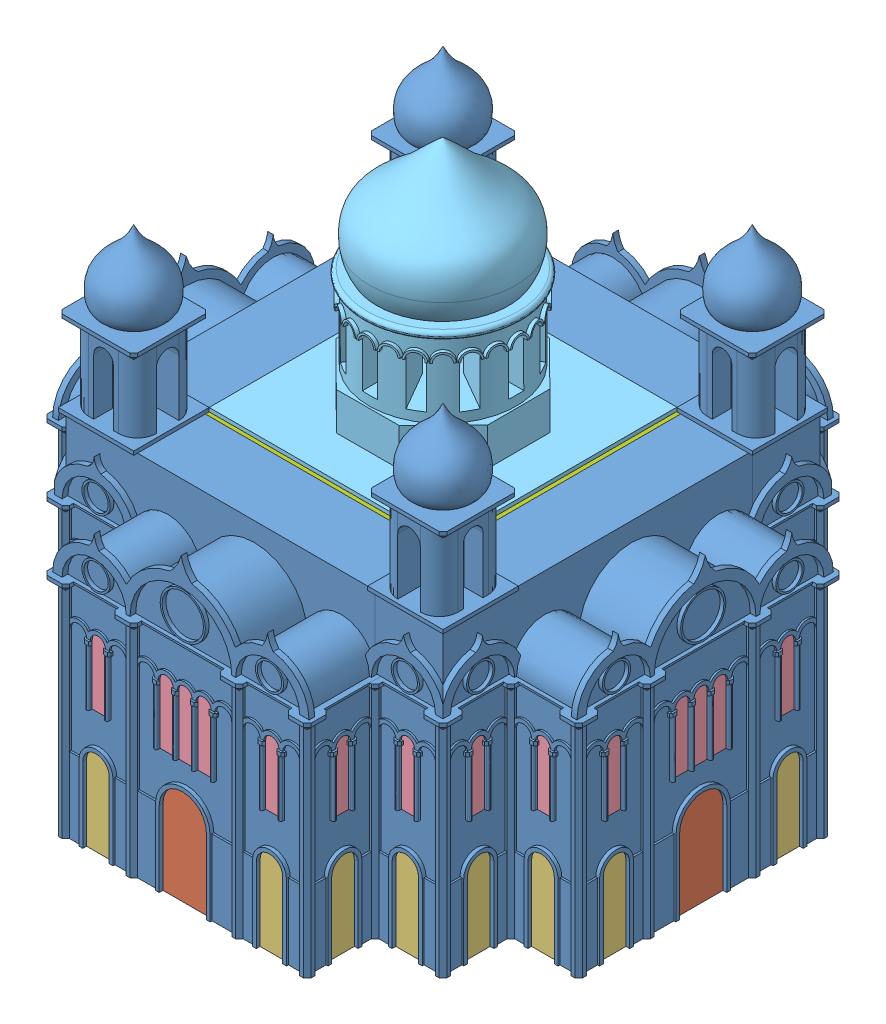
SolidWorks assembly Assem6, configuration Default. Lengths in mm.
Overall size (142 142.08 142).
71 component instances, 7 part files, 159 mates.
Components (placement in the parent):
- a4-object-wall-1: a4-object-wall [Default] at (90 0 -530.3215) x (0 0 -1) z (1 0 0) size (88 122 41)
- a4-object-bigDoor-3: a4-object-bigDoor [Default] at (117 0 -486.5715) x (0 0 -1) z (1 0 0) size (12.5 26.25 1)
- a4-object-smallDoor-1: a4-object-smallDoor [Default] at (100 0 -435.8215) x (0 0 1) z (0 -1 0) size (7 1 23.5)
- a4-object-smallDoor-2: a4-object-smallDoor [Default] at (117 0 -460.8215) x (0 0 -1) z (0 -1 0) size (7 1 23.5)
- a4-object-smallDoor-3: a4-object-smallDoor [Default] at (117 0 -506.8215) x (0 0 -1) z (0 -1 0) size (7 1 23.5)
- a4-object-smallDoor-4: a4-object-smallDoor [Default] at (105.5 0 -511.3215) x (-1 0 0) z (0 -1 0) size (7 1 23.5)
- a4-object-smallDoor-6: a4-object-smallDoor [Default] at (105.5 0 -448.3215) x (-1 0 0) z (0 -1 0) size (7 1 23.5)
- a4-object-smallDoor-7: a4-object-smallDoor [Default] at (94.5 0 -431.3215) x (1 0 0) z (0 -1 0) size (7 1 23.5)
- a4-object-window-1: a4-object-window [Default] at (93 32.25 -431.3215) size (4 18 1)
- a4-object-window-2: a4-object-window [Default] at (118 32.25 -473.3215) x (0 0 1) z (-1 0 0) size (4 18 1)
- a4-object-window-3: a4-object-window [Default] at (111 32.25 -449.3215) size (4 18 1)
- a4-object-window-4: a4-object-window [Default] at (117 32.25 -459.3215) x (0 0 -1) z (1 0 0) size (4 18 1)
- a4-object-window-5: a4-object-window [Default] at (99 32.25 -441.3215) x (0 0 -1) z (1 0 0) size (4 18 1)
- a4-object-window-8: a4-object-window [Default] at (111 32.25 -512.3215) size (4 18 1)
- a4-object-window-10: a4-object-window [Default] at (117 32.25 -482.3215) x (0 0 -1) z (1 0 0) size (4 18 1)
- a4-object-window-11: a4-object-window [Default] at (117 32.25 -505.3215) x (0 0 -1) z (1 0 0) size (4 18 1)
- a4-object-wall-6: a4-object-wall [Default] at (0 0 -520.3215) x (-1 0 0) z (0 0 -1) size (88 122 41)
- a4-object-window-12: a4-object-window [Default] at (25 32.25 -547.3215) x (-1 0 0) z (0 0 -1) size (4 18 1)
- a4-object-window-13: a4-object-window [Default] at (47 32.2593 -548.3215) x (1 0 0) z (0 -0.009348 0.999956) size (4 18 1)
- a4-object-window-14: a4-object-window [Default] at (48 32.25 -547.3215) x (-1 0 0) z (0 0 -1) size (4 18 1)
- a4-object-smallDoor-14: a4-object-smallDoor [Default] at (99 0 -524.8215) x (0 0 -1) z (0 -1 0) size (7 1 23.5)
- a4-object-window-15: a4-object-window [Default] at (18 32.25 -541.3215) x (0 0 -1) z (1 0 0) size (4 18 1)
- a4-object-window-16: a4-object-window [Default] at (81 32.25 -541.3215) x (0 0 -1) z (1 0 0) size (4 18 1)
- a4-object-window-17: a4-object-window [Default] at (57 32.25 -548.3215) size (4 18 1)
- a4-object-window-18: a4-object-window [Default] at (89 32.25 -529.3215) x (-1 0 0) z (0 0 -1) size (4 18 1)
- a4-object-window-19: a4-object-window [Default] at (71 32.25 -547.3215) x (-1 0 0) z (0 0 -1) size (4 18 1)
- a4-object-window-20: a4-object-window [Default] at (99 32.25 -523.3215) x (0 0 -1) z (1 0 0) size (4 18 1)
- a4-object-bigDoor-6: a4-object-bigDoor [Default] at (43.75 0 -547.3215) x (-1 0 0) z (0 0.009348 -0.999956) size (12.5 26.25 1)
- a4-object-smallDoor-15: a4-object-smallDoor [Default] at (69.5 0 -547.3215) x (-1 0 0) z (0 -1 0) size (7 1 23.5)
- a4-object-smallDoor-16: a4-object-smallDoor [Default] at (23.5 0 -547.3215) x (-1 0 0) z (0 -1 0) size (7 1 23.5)
- a4-object-smallDoor-17: a4-object-smallDoor [Default] at (19 0 -535.8215) x (0 0 1) z (0 -1 0) size (7 1 23.5)
- a4-object-smallDoor-18: a4-object-smallDoor [Default] at (82 0 -535.8215) x (0 0 1) z (0 -1 0) size (7 1 23.5)
- a4-object-smallDoor-19: a4-object-smallDoor [Default] at (94.5 0 -530.3215) x (1 0 0) z (0 -1 0) size (7 1 23.5)
- a4-object-wall-7: a4-object-wall [Default] at (100 0 -440.3215) size (88 122 41)
- a4-object-window-21: a4-object-window [Default] at (75 32.25 -413.3215) size (4 18 1)
- a4-object-window-22: a4-object-window [Default] at (53 32.25 -412.3215) x (-1 0 0) z (0 0 -1) size (4 18 1)
- a4-object-window-23: a4-object-window [Default] at (52 32.25 -413.3215) size (4 18 1)
- a4-object-smallDoor-20: a4-object-smallDoor [Default] at (1 0 -435.8215) x (0 0 1) z (0 -1 0) size (7 1 23.5)
- a4-object-window-24: a4-object-window [Default] at (82 32.25 -419.3215) x (0 0 1) z (-1 0 0) size (4 18 1)
- a4-object-window-25: a4-object-window [Default] at (19 32.25 -419.3215) x (0 0 1) z (-1 0 0) size (4 18 1)
- a4-object-window-26: a4-object-window [Default] at (43 32.25 -412.3215) x (-1 0 0) z (0 0 -1) size (4 18 1)
- a4-object-window-27: a4-object-window [Default] at (11 32.25 -431.3215) size (4 18 1)
- a4-object-window-28: a4-object-window [Default] at (29 32.25 -413.3215) size (4 18 1)
- a4-object-window-29: a4-object-window [Default] at (1 32.25 -437.3215) x (0 0 1) z (-1 0 0) size (4 18 1)
- a4-object-bigDoor-7: a4-object-bigDoor [Default] at (56.25 0 -413.3215) size (12.5 26.25 1)
- a4-object-smallDoor-21: a4-object-smallDoor [Default] at (30.5 0 -413.3215) x (1 0 0) z (0 -1 0) size (7 1 23.5)
- a4-object-smallDoor-22: a4-object-smallDoor [Default] at (76.5 0 -413.3215) x (1 0 0) z (0 -1 0) size (7 1 23.5)
- a4-object-smallDoor-23: a4-object-smallDoor [Default] at (81 0 -424.8215) x (0 0 -1) z (0 -1 0) size (7 1 23.5)
- a4-object-smallDoor-24: a4-object-smallDoor [Default] at (18 0 -424.8215) x (0 0 -1) z (0 -1 0) size (7 1 23.5)
- a4-object-smallDoor-25: a4-object-smallDoor [Default] at (5.5 0 -430.3215) x (-1 0 0) z (0 -1 0) size (7 1 23.5)
- a4-object-wall-8: a4-object-wall [Default] at (10 0 -430.3215) x (0 0 1) z (-1 0 0) size (88 122 41)
- a4-object-window-30: a4-object-window [Default] at (-17 32.25 -455.3215) x (0 0 1) z (-1 0 0) size (4 18 1)
- a4-object-window-31: a4-object-window [Default] at (-18 32.25 -477.3215) x (0 0 -1) z (1 0 0) size (4 18 1)
- a4-object-window-32: a4-object-window [Default] at (-17 32.25 -478.3215) x (0 0 1) z (-1 0 0) size (4 18 1)
- a4-object-smallDoor-26: a4-object-smallDoor [Default] at (5.5 0 -529.3215) x (-1 0 0) z (0 -1 0) size (7 1 23.5)
- a4-object-window-33: a4-object-window [Default] at (-11 32.25 -448.3215) x (-1 0 0) z (0 0 -1) size (4 18 1)
- a4-object-window-34: a4-object-window [Default] at (-11 32.25 -511.3215) x (-1 0 0) z (0 0 -1) size (4 18 1)
- a4-object-window-35: a4-object-window [Default] at (-18 32.25 -487.3215) x (0 0 -1) z (1 0 0) size (4 18 1)
- a4-object-window-36: a4-object-window [Default] at (1 32.25 -519.3215) x (0 0 1) z (-1 0 0) size (4 18 1)
- a4-object-window-37: a4-object-window [Default] at (-17 32.25 -501.3215) x (0 0 1) z (-1 0 0) size (4 18 1)
- a4-object-window-38: a4-object-window [Default] at (7 32.25 -529.3215) x (-1 0 0) z (0 0 -1) size (4 18 1)
- a4-object-bigDoor-8: a4-object-bigDoor [Default] at (-17 0 -474.0715) x (0 0 1) z (-1 0 0) size (12.5 26.25 1)
- a4-object-smallDoor-27: a4-object-smallDoor [Default] at (-17 0 -499.8215) x (0 0 1) z (0 -1 0) size (7 1 23.5)
- a4-object-smallDoor-28: a4-object-smallDoor [Default] at (-17 0 -453.8215) x (0 0 1) z (0 -1 0) size (7 1 23.5)
- a4-object-smallDoor-29: a4-object-smallDoor [Default] at (-5.5 0 -449.3215) x (1 0 0) z (0 -1 0) size (7 1 23.5)
- a4-object-smallDoor-30: a4-object-smallDoor [Default] at (-5.5 0 -512.3215) x (1 0 0) z (0 -1 0) size (7 1 23.5)
- a4-object-smallDoor-31: a4-object-smallDoor [Default] at (0 0 -524.8215) x (0 0 -1) z (0 -1 0) size (7 1 23.5)
- a4-object-top-1: a4-object-top [Default] at (81.0013 79.0812 -511.3215) x (0.999999 0.00131 0) z (0 0 1) size (62 63 62)
- a4-object-window-39: a4-object-window [Default] at (118 32.25 -483.3392) x (0 0 1) z (-1 0 0) size (4 18 1)
- a4-object-floor-2: a4-object-floor [Default] at (81 0 -547.3215) size (134 2 134)
- a4-object-roof-1: a4-object-roof [Default] at (82 77 -512.3215) size (64 2 64)
Mates (geometry in assembly coordinates):
- Coincident19: coincident: point of walltest5-1; point of bigDoor-3
- Coincident24: coincident anti-aligned: plane of walltest5-1 through (117 0 -499.8215) normal (0 0 -1); plane of smallDoor-3 through (118 0 -499.8215) normal (0 0 1)
- Coincident25: coincident: point of walltest5-1; point of smallDoor-3
- Concentric1: concentric anti-aligned: cylinder of walltest5-1 through (117 20 -503.3215) axis (1 0 0) radius 3.5; cylinder of smallDoor-3 through (118 20 -503.3215) axis (-1 0 0) radius 3.5
- Coincident26: coincident: point of walltest5-1; point of smallDoor-4
- Concentric2: concentric aligned: cylinder of walltest5-1 through (109 20 -513.3215) axis (0 0 1) radius 3.5; cylinder of smallDoor-4 through (109 20 -512.3215) axis (0 0 1) radius 3.5
- Concentric4: concentric anti-aligned: cylinder of walltest5-1 through (117 20 -457.3215) axis (1 0 0) radius 3.5; cylinder of smallDoor-2 through (118 20 -457.3215) axis (-1 0 0) radius 3.5
- Coincident30: coincident: point of walltest5-1; point of smallDoor-2
- Concentric5: concentric anti-aligned: cylinder of walltest5-1 through (109 20 -447.3215) axis (0 0 -1) radius 3.5; cylinder of smallDoor-6 through (109 20 -449.3215) axis (0 0 1) radius 3.5
- Coincident31: coincident: point of walltest5-1; point of smallDoor-6
- Concentric6: concentric anti-aligned: cylinder of walltest5-1 through (101 20 -439.3215) axis (-1 0 0) radius 3.5; cylinder of smallDoor-1 through (99 20 -439.3215) axis (1 0 0) radius 3.5
- Coincident32: coincident: point of walltest5-1; point of smallDoor-1
- Concentric7: concentric anti-aligned: cylinder of walltest5-1 through (91 20 -431.3215) axis (0 0 1) radius 3.5; cylinder of smallDoor-7 through (91 20 -430.3215) axis (0 0 -1) radius 3.5
- Coincident33: coincident: point of walltest5-1; point of smallDoor-7
- Concentric14: concentric anti-aligned: cylinder of walltest5-1 through (91 48.25 -431.3215) axis (0 0 1) radius 2; cylinder of window-1 through (91 48.25 -430.3215) axis (0 0 -1) radius 2
- Coincident42: coincident: point of window-1; point of walltest5-1
- Concentric15: concentric anti-aligned: cylinder of walltest5-1 through (99 48.25 -439.3215) axis (1 0 0) radius 2; cylinder of window-5 through (100 48.25 -439.3215) axis (-1 0 0) radius 2
- Coincident43: coincident: point of window-5; point of walltest5-1
- Concentric16: concentric anti-aligned: cylinder of walltest5-1 through (109 48.25 -449.3215) axis (0 0 1) radius 2; cylinder of window-3 through (109 48.25 -448.3215) axis (0 0 -1) radius 2
- Coincident44: coincident: point of walltest5-1; point of window-3
- Concentric17: concentric anti-aligned: cylinder of walltest5-1 through (117.5 48.25 -457.3215) axis (1 0 0) radius 2; cylinder of window-4 through (118 48.25 -457.3215) axis (-1 0 0) radius 2
- Coincident45: coincident: point of walltest5-1; point of window-4
- Concentric18: concentric anti-aligned: cylinder of walltest5-1 through (118.5 48.25 -475.3215) axis (-1 0 0) radius 2; cylinder of window-2 through (117 48.25 -475.3215) axis (1 0 0) radius 2
- Coincident46: coincident: point of walltest5-1; point of window-2
- Coincident47: coincident anti-aligned: circle of walltest5-1; cylinder of window-10 through (118 48.25 -480.3215) axis (-1 0 0) radius 2
- Coincident48: coincident: point of walltest5-1; point of window-10
- Coincident51: coincident: point of a4-object-wall-1; point of window-9
- Concentric20: concentric anti-aligned: cylinder of walltest5-1 through (117.5 48.25 -503.3215) axis (1 0 0) radius 2; cylinder of window-11 through (118 48.25 -503.3215) axis (-1 0 0) radius 2
- Coincident52: coincident: point of walltest5-1; point of window-11
- Concentric21: concentric aligned: cylinder of walltest5-1 through (109 48.25 -511.3215) axis (0 0 -1) radius 2; cylinder of window-8 through (109 48.25 -511.3215) axis (0 0 -1) radius 2
- Coincident53: coincident: point of walltest5-1; point of window-8
- Coincident54: coincident: point of walltest5-6; point of smallDoor-16
- Coincident55: coincident anti-aligned: plane of walltest5-6 through (30.5 0 -547.3215) normal (-1 0 0); plane of smallDoor-16 through (30.5 0 -548.3215) normal (1 0 0)
- Concentric22: concentric anti-aligned: cylinder of walltest5-6 through (73 48.25 -547.8215) axis (0 0 -1) radius 2; cylinder of window-19 through (73 48.25 -548.3215) axis (0 0 1) radius 2
- Coincident56: coincident: point of walltest5-6; point of window-14
- Coincident57: coincident: point of walltest5-6; point of window-19
- Concentric23: concentric anti-aligned: cylinder of walltest5-6 through (55 48.25 -548.8215) axis (0 0 1) radius 2; cylinder of window-17 through (55 48.25 -547.3215) axis (0 0 -1) radius 2
- Coincident58: coincident: point of walltest5-6; point of window-17
- Coincident59: coincident anti-aligned: circle of walltest5-6; cylinder of window-14 through (50 48.25 -548.3215) axis (0 0 1) radius 2
- Coincident60: coincident: point of walltest5-6; point of window-18
- Concentric24: concentric anti-aligned: cylinder of walltest5-6 through (91 48.25 -529.3215) axis (0 0 -1) radius 2; cylinder of window-18 through (91 48.25 -530.3215) axis (0 0 1) radius 2
- Concentric25: concentric anti-aligned: cylinder of walltest5-6 through (99 20 -521.3215) axis (1 0 0) radius 3.5; cylinder of smallDoor-14 through (100 20 -521.3215) axis (-1 0 0) radius 3.5
- Coincident61: coincident: point of walltest5-6; point of smallDoor-14
- Coincident62: coincident: point of walltest5-6; point of smallDoor-18
- Concentric26: concentric anti-aligned: cylinder of walltest5-6 through (91 20 -531.3215) axis (0 0 1) radius 3.5; cylinder of smallDoor-19 through (91 20 -529.3215) axis (0 0 -1) radius 3.5
- Coincident63: coincident: point of walltest5-6; point of smallDoor-19
- Concentric27: concentric anti-aligned: cylinder of walltest5-6 through (99 48.25 -521.3215) axis (1 0 0) radius 2; cylinder of window-20 through (100 48.25 -521.3215) axis (-1 0 0) radius 2
- Concentric28: concentric aligned: cylinder of walltest5-6 through (17 20 -539.3215) axis (1 0 0) radius 3.5; cylinder of smallDoor-17 through (18 20 -539.3215) axis (1 0 0) radius 3.5
- Coincident64: coincident: point of walltest5-6; point of smallDoor-17
- Concentric29: concentric anti-aligned: cylinder of walltest5-6 through (83 20 -539.3215) axis (-1 0 0) radius 3.5; cylinder of smallDoor-18 through (81 20 -539.3215) axis (1 0 0) radius 3.5
- Concentric30: concentric anti-aligned: cylinder of walltest5-6 through (27 20 -547.3215) axis (0 0 -1) radius 3.5; cylinder of smallDoor-16 through (27 20 -548.3215) axis (0 0 1) radius 3.5
- Concentric31: concentric anti-aligned: cylinder of walltest5-6 through (73 20 -547.3215) axis (0 0 -1) radius 3.5; cylinder of smallDoor-15 through (73 20 -548.3215) axis (0 0 1) radius 3.5
- Coincident65: coincident: point of walltest5-6; point of smallDoor-15
- Coincident66: coincident: point of walltest5-6; point of window-12
- Coincident67: coincident: point of walltest5-6; point of window-16
- Coincident68: coincident: point of walltest5-6; point of bigDoor-6
- Concentric32: concentric anti-aligned: cylinder of walltest5-6 through (81 48.25 -539.3215) axis (1 0 0) radius 2; cylinder of window-16 through (82 48.25 -539.3215) axis (-1 0 0) radius 2
- Concentric33: concentric anti-aligned: cylinder of walltest5-6 through (27 48.25 -547.8215) axis (0 0 -1) radius 2; cylinder of window-12 through (27 48.25 -548.3215) axis (0 0 1) radius 2
- Coincident69: coincident: point of walltest5-6; point of window-13
- Coincident70: coincident: point of walltest5-6; point of window-20
- Concentric34: concentric aligned: cylinder of walltest5-6 through (19 48.25 -539.3215) axis (-1 0 0) radius 2; cylinder of window-15 through (19 48.25 -539.3215) axis (-1 0 0) radius 2
- Coincident71: coincident: point of walltest5-6; point of window-15
- Coincident72: coincident: point of walltest5-7; point of smallDoor-22
- Coincident73: coincident anti-aligned: plane of walltest5-7 through (69.5 0 -413.3215) normal (1 0 0); plane of smallDoor-22 through (69.5 0 -412.3215) normal (-1 0 0)
- Concentric35: concentric anti-aligned: cylinder of walltest5-7 through (27 48.25 -412.8215) axis (0 0 1) radius 2; cylinder of window-28 through (27 48.25 -412.3215) axis (0 0 -1) radius 2
- Coincident74: coincident: point of walltest5-7; point of window-23
- Coincident75: coincident: point of walltest5-7; point of window-28
- Concentric36: concentric anti-aligned: cylinder of walltest5-7 through (45 48.25 -411.8215) axis (0 0 -1) radius 2; cylinder of window-26 through (45 48.25 -413.3215) axis (0 0 1) radius 2
- Coincident76: coincident: point of walltest5-7; point of window-26
- Coincident77: coincident anti-aligned: circle of walltest5-7; cylinder of window-23 through (50 48.25 -412.3215) axis (0 0 -1) radius 2
- Coincident78: coincident: point of walltest5-7; point of window-27
- Concentric37: concentric anti-aligned: cylinder of walltest5-7 through (9 48.25 -431.3215) axis (0 0 1) radius 2; cylinder of window-27 through (9 48.25 -430.3215) axis (0 0 -1) radius 2
- Concentric38: concentric anti-aligned: cylinder of walltest5-7 through (1 20 -439.3215) axis (-1 0 0) radius 3.5; cylinder of smallDoor-20 through (0 20 -439.3215) axis (1 0 0) radius 3.5
- Coincident79: coincident: point of walltest5-7; point of smallDoor-20
- Coincident80: coincident: point of walltest5-7; point of smallDoor-24
- Concentric39: concentric anti-aligned: cylinder of walltest5-7 through (9 20 -429.3215) axis (0 0 -1) radius 3.5; cylinder of smallDoor-25 through (9 20 -431.3215) axis (0 0 1) radius 3.5
- Coincident81: coincident: point of walltest5-7; point of smallDoor-25
- Concentric40: concentric anti-aligned: cylinder of walltest5-7 through (1 48.25 -439.3215) axis (-1 0 0) radius 2; cylinder of window-29 through (0 48.25 -439.3215) axis (1 0 0) radius 2
- Concentric41: concentric aligned: cylinder of walltest5-7 through (83 20 -421.3215) axis (-1 0 0) radius 3.5; cylinder of smallDoor-23 through (82 20 -421.3215) axis (-1 0 0) radius 3.5
- Coincident82: coincident: point of walltest5-7; point of smallDoor-23
- Concentric42: concentric anti-aligned: cylinder of walltest5-7 through (17 20 -421.3215) axis (1 0 0) radius 3.5; cylinder of smallDoor-24 through (19 20 -421.3215) axis (-1 0 0) radius 3.5
- Concentric43: concentric anti-aligned: cylinder of walltest5-7 through (73 20 -413.3215) axis (0 0 1) radius 3.5; cylinder of smallDoor-22 through (73 20 -412.3215) axis (0 0 -1) radius 3.5
- Concentric44: concentric anti-aligned: cylinder of walltest5-7 through (27 20 -413.3215) axis (0 0 1) radius 3.5; cylinder of smallDoor-21 through (27 20 -412.3215) axis (0 0 -1) radius 3.5
- Coincident83: coincident: point of walltest5-7; point of smallDoor-21
- Coincident84: coincident: point of walltest5-7; point of window-21
- Coincident85: coincident: point of walltest5-7; point of window-25
- Coincident86: coincident: point of walltest5-7; point of bigDoor-7
- Concentric45: concentric anti-aligned: cylinder of walltest5-7 through (19 48.25 -421.3215) axis (-1 0 0) radius 2; cylinder of window-25 through (18 48.25 -421.3215) axis (1 0 0) radius 2
- Concentric46: concentric anti-aligned: cylinder of walltest5-7 through (73 48.25 -412.8215) axis (0 0 1) radius 2; cylinder of window-21 through (73 48.25 -412.3215) axis (0 0 -1) radius 2
- Coincident87: coincident: point of walltest5-7; point of window-22
- Coincident88: coincident: point of walltest5-7; point of window-29
- Concentric47: concentric aligned: cylinder of walltest5-7 through (81 48.25 -421.3215) axis (1 0 0) radius 2; cylinder of window-24 through (81 48.25 -421.3215) axis (1 0 0) radius 2
- Coincident89: coincident: point of walltest5-7; point of window-24
- Coincident90: coincident: point of walltest5-8; point of smallDoor-28
- Coincident91: coincident anti-aligned: plane of walltest5-8 through (-17 0 -460.8215) normal (0 0 1); plane of smallDoor-28 through (-18 0 -460.8215) normal (0 0 -1)
- Concentric48: concentric anti-aligned: cylinder of walltest5-8 through (-17.5 48.25 -503.3215) axis (-1 0 0) radius 2; cylinder of window-37 through (-18 48.25 -503.3215) axis (1 0 0) radius 2
- Coincident92: coincident: point of walltest5-8; point of window-32
- Coincident93: coincident: point of walltest5-8; point of window-37
- Concentric49: concentric anti-aligned: cylinder of walltest5-8 through (-18.5 48.25 -485.3215) axis (1 0 0) radius 2; cylinder of window-35 through (-17 48.25 -485.3215) axis (-1 0 0) radius 2
- Coincident94: coincident: point of walltest5-8; point of window-35
- Coincident95: coincident anti-aligned: circle of walltest5-8; cylinder of window-32 through (-18 48.25 -480.3215) axis (1 0 0) radius 2
- Coincident96: coincident: point of walltest5-8; point of window-36
- Concentric50: concentric anti-aligned: cylinder of walltest5-8 through (1 48.25 -521.3215) axis (-1 0 0) radius 2; cylinder of window-36 through (0 48.25 -521.3215) axis (1 0 0) radius 2
- Concentric51: concentric anti-aligned: cylinder of walltest5-8 through (9 20 -529.3215) axis (0 0 -1) radius 3.5; cylinder of smallDoor-26 through (9 20 -530.3215) axis (0 0 1) radius 3.5
- Coincident97: coincident: point of walltest5-8; point of smallDoor-26
- Coincident98: coincident: point of walltest5-8; point of smallDoor-30
- Concentric52: concentric anti-aligned: cylinder of walltest5-8 through (-1 20 -521.3215) axis (1 0 0) radius 3.5; cylinder of smallDoor-31 through (1 20 -521.3215) axis (-1 0 0) radius 3.5
- Coincident99: coincident: point of walltest5-8; point of smallDoor-31
- Concentric53: concentric anti-aligned: cylinder of walltest5-8 through (9 48.25 -529.3215) axis (0 0 -1) radius 2; cylinder of window-38 through (9 48.25 -530.3215) axis (0 0 1) radius 2
- Concentric54: concentric aligned: cylinder of walltest5-8 through (-9 20 -447.3215) axis (0 0 -1) radius 3.5; cylinder of smallDoor-29 through (-9 20 -448.3215) axis (0 0 -1) radius 3.5
- Coincident100: coincident: point of walltest5-8; point of smallDoor-29
- Concentric55: concentric anti-aligned: cylinder of walltest5-8 through (-9 20 -513.3215) axis (0 0 1) radius 3.5; cylinder of smallDoor-30 through (-9 20 -511.3215) axis (0 0 -1) radius 3.5
- Concentric56: concentric anti-aligned: cylinder of walltest5-8 through (-17 20 -457.3215) axis (-1 0 0) radius 3.5; cylinder of smallDoor-28 through (-18 20 -457.3215) axis (1 0 0) radius 3.5
- Concentric57: concentric anti-aligned: cylinder of walltest5-8 through (-17 20 -503.3215) axis (-1 0 0) radius 3.5; cylinder of smallDoor-27 through (-18 20 -503.3215) axis (1 0 0) radius 3.5
- Coincident101: coincident: point of walltest5-8; point of smallDoor-27
- Coincident102: coincident: point of walltest5-8; point of window-30
- Coincident103: coincident: point of walltest5-8; point of window-34
- Coincident104: coincident: point of walltest5-8; point of bigDoor-8
- Concentric58: concentric anti-aligned: cylinder of walltest5-8 through (-9 48.25 -511.3215) axis (0 0 -1) radius 2; cylinder of window-34 through (-9 48.25 -512.3215) axis (0 0 1) radius 2
- Concentric59: concentric anti-aligned: cylinder of walltest5-8 through (-17.5 48.25 -457.3215) axis (-1 0 0) radius 2; cylinder of window-30 through (-18 48.25 -457.3215) axis (1 0 0) radius 2
- Coincident105: coincident: point of walltest5-8; point of window-31
- Coincident106: coincident: point of walltest5-8; point of window-38
- Concentric60: concentric aligned: cylinder of walltest5-8 through (-9 48.25 -449.3215) axis (0 0 1) radius 2; cylinder of window-33 through (-9 48.25 -449.3215) axis (0 0 1) radius 2
- Coincident107: coincident: point of walltest5-8; point of window-33
- Coincident108: coincident anti-aligned: plane of walltest5-1 through (118 0 -512.3215) normal (0 0 -1); plane of walltest5-6 through (27 60 -512.3215) normal (0 0 1)
- Coincident109: coincident aligned: line of walltest5-1 through (100 79 -512.3215) axis (0 -1 0); line of walltest5-6 through (100 79 -512.3215) axis (0 -1 0)
- Coincident110: coincident aligned: line of walltest5-1 through (82 79 -512.3215) axis (1 0 0); line of walltest5-6 through (81 79 -512.3215) axis (1 0 0)
- Coincident111: coincident: point of walltest5-6; point of bigDoor-6
- Coincident112: coincident: point of walltest5-6; point of window-13
- Coincident113: coincident anti-aligned: plane of walltest5-1 through (82 60 -503.3215) normal (-1 0 0); plane of walltest5-7 through (82 0 -412.3215) normal (1 0 0)
- Coincident114: coincident aligned: line of walltest5-1 through (82 79 -430.3215) axis (0 -1 0); line of walltest5-7 through (82 79 -430.3215) axis (0 -1 0)
- Coincident115: coincident aligned: line of walltest5-1 through (82 79 -449.3215) axis (0 0 1); line of walltest5-7 through (82 79 -448.3215) axis (0 0 1)
- Coincident116: coincident anti-aligned: plane of walltest5-6 through (18 0 -548.3215) normal (-1 0 0); plane of walltest5-8 through (18 60 -457.3215) normal (1 0 0)
- Coincident117: coincident aligned: line of walltest5-7 through (0 79 -448.3215) axis (0 -1 0); line of walltest5-8 through (0 79 -448.3215) axis (0 -1 0)
- Coincident118: coincident aligned: line of walltest5-6 through (18 79 -530.3215) axis (0 -1 0); line of walltest5-8 through (18 79 -530.3215) axis (0 -1 0)
- Coincident119: coincident: point of walltest5-8; point of bigDoor-8
- Concentric61: concentric anti-aligned: cylinder of walltest5-8 through (-17 20 -480.3215) axis (-1 0 0) radius 6.25; cylinder of bigDoor-8 through (-18 20 -480.3215) axis (1 0 0) radius 6.25
- Concentric62: concentric anti-aligned: cylinder of walltest5-7 through (50 20 -413.3215) axis (0 0 1) radius 6.25; cylinder of bigDoor-7 through (50 20 -412.3215) axis (0 0 -1) radius 6.25
- Parallel4: parallel anti-aligned: cylinder of walltest5-7 through (55.0088 48.2522 -411.8215) axis (0 0 -1) radius 2.0088; cylinder of window-22 through (55 48.25 -413.3215) axis (0 0 1) radius 2
- Parallel5: parallel anti-aligned: cylinder of walltest5-8 through (-18.5 48.2522 -475.3127) axis (1 0 0) radius 2.0088; cylinder of window-31 through (-17 48.25 -475.3215) axis (-1 0 0) radius 2
- Concentric65: concentric anti-aligned: cylinder of walltest5-1 through (117 20 -480.3215) axis (1 0 0) radius 6.25; cylinder of bigDoor-3 through (118 20 -480.3215) axis (-1 0 0) radius 6.25
- Parallel6: parallel anti-aligned: cylinder of a4-object-wall-1 through (118.5 48.2522 -485.3303) axis (-1 0 0) radius 2.0088; cylinder of window-9 through (-23.2406 56.8416 -5.526) axis (1 0 0) radius 2
- Coincident122: coincident anti-aligned: line of a4-object-wall-1 through (82 79 -512.3215) axis (0 0 1); line of floor-1 through (82 79 -448.3215) axis (0 0 -1)
- Coincident123: coincident: point of walltest5-7; point of top1-1
- Coincident124: coincident: point of walltest5-8; point of top1-1
- Coincident125: coincident anti-aligned: line of walltest5-7 through (53 48.25 -411.8215) axis (0 0 -1); line of window-22 through (53 48.25 -413.3215) axis (0 0 1)
- Coincident126: coincident anti-aligned: line of walltest5-8 through (-18.5 48.25 -477.3215) axis (1 0 0); line of window-31 through (-17 48.25 -477.3215) axis (-1 0 0)
- Coincident129: coincident anti-aligned: line of walltest5-1 through (118.5 48.25 -487.3392) axis (-1 0 0); line of window-39 through (117 48.25 -487.3392) axis (1 0 0)
- Coincident130: coincident anti-aligned: line of walltest5-1 through (117 32.25 -483.3215) axis (0 0 -1); line of window-39 through (117 32.25 -487.3392) axis (0 0 1)
- Parallel7: parallel anti-aligned: line of walltest5-1 through (117 0 -499.8215) axis (0 0 1); line of floor2-1 through (117 0 -449.3215) axis (0 0 -1)
- Coincident133: coincident anti-aligned: line of walltest5-8 through (-17 0 -460.8215) axis (0 0 -1); line of floor2-1 through (-17 0 -511.3215) axis (0 0 1)
- Coincident134: coincident anti-aligned: line of walltest5-7 through (43.75 0 -413.3215) axis (-1 0 0); line of floor2-1 through (19 0 -413.3215) axis (1 0 0)
- Parallel8: parallel anti-aligned: line of walltest5-8 through (12.5 0 -529.3215) axis (1 0 0); line of floor2-1 through (19 0 -529.3215) axis (-1 0 0)
- Parallel9: parallel anti-aligned: line of walltest5-8 through (12.5 0 -529.3215) axis (1 0 0); line of floor2-1 through (19 0 -529.3215) axis (-1 0 0)
- Coincident136: coincident anti-aligned: plane of floor2-1 through (81 0 -547.3215) normal (0 -1 0)
- Coincident137: coincident anti-aligned: plane of walltest5-8 through (0 80 -530.3215) normal (-1 0 0)
- Coincident138: coincident: point of a4-object-top-1; point of window-40
- Coincident140: coincident anti-aligned: line of a4-object-wall-6 through (18 79 -512.3215) axis (1 0 0); line of a4-object-roof-1 through (83.957 78.9712 -504.1831) axis (-1 0 0)
- Coincident141: coincident anti-aligned: line of a4-object-wall-8 through (18 79 -448.3215) axis (0 0 -1); line of a4-object-roof-1 through (18 79 -512.3215) axis (0 0 1)
